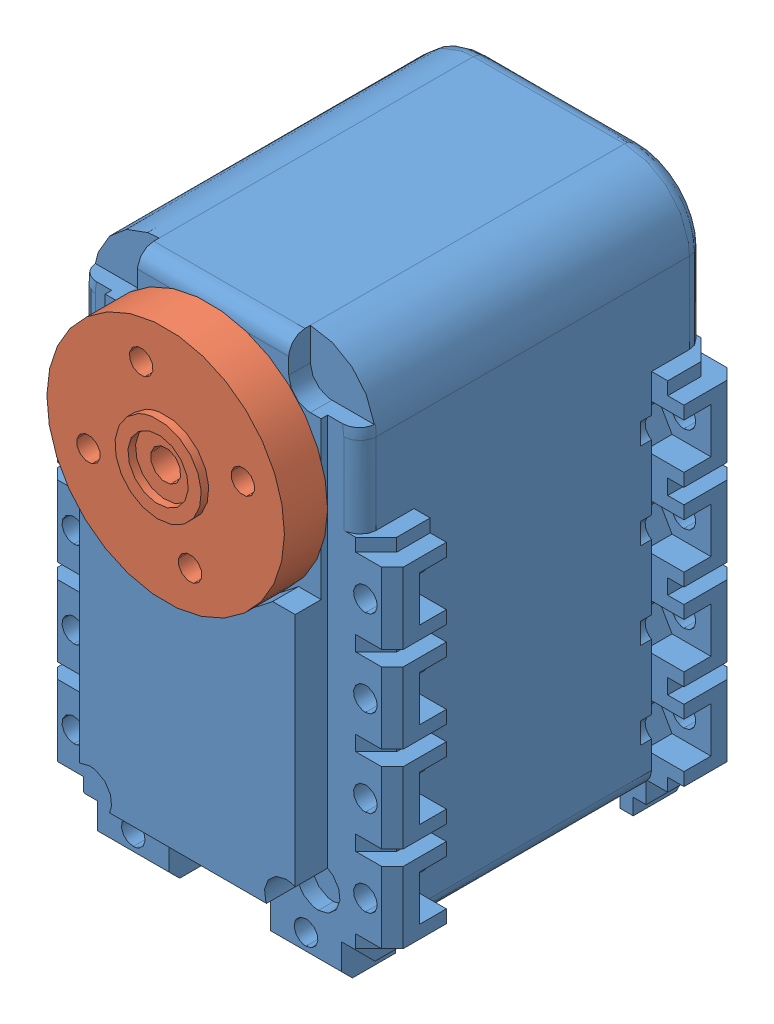
SolidWorks assembly Assemblage1, configuration Default. Lengths in mm.
Overall size (32 52.31 40.7).
2 component instances, 2 part files, 2 mates.
Components (placement in the parent):
- AX-12_modif-1: AX-12_modif [Défaut] at (-2.6768 21.8769 -4.3025) size (32 50.06 38.01)
- attache_ax-12-1: attache_ax-12 [Default] at (-2.6768 21.8769 12.6975) x (-0.301968 0.953318 0) z (0 0 1) size (22 22 4.7)
Mates (geometry in assembly coordinates):
- Coïncidente1: coincident: plane of AX-12_modif-1 through (8.7632 10.4369 12.6975) normal (0 0 1); plane of attache_ax-12-1 through (-2.6768 21.8769 12.6975) normal (0 0 -1)
- Tangent6: tangent: face of AX-12_modif-1; cylinder of attache_ax-12-1
